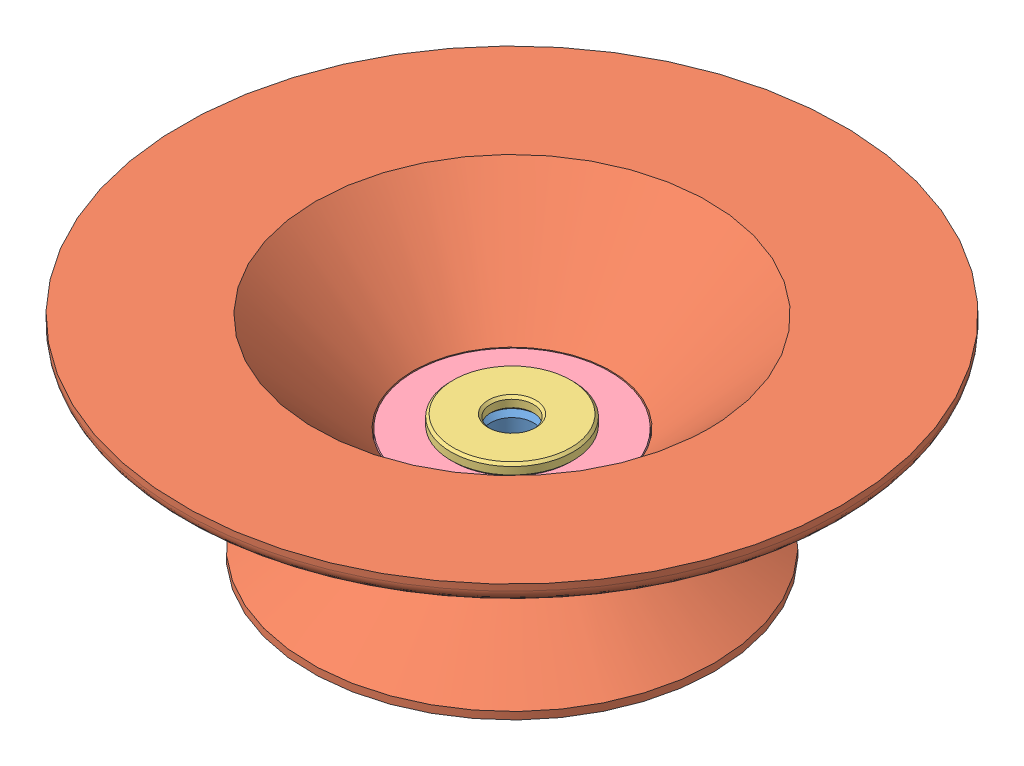
SolidWorks assembly Assem1, configuration Default. Lengths in mm.
Overall size (53.93 18.5 53.93).
4 component instances, 4 part files, 6 mates.
Components (placement in the parent):
- standoff-1: standoff [Default] at origin size (12 10.5 12)
- outer guide-1: outer guide [Default] at (0 8 0) x (1 0 0) z (0 -1 0) size (53.93 53.93 17.5)
- washer-1: washer [Default] at (0 11.5 0) x (1 0 0) z (0 -1 0) size (10 10 1)
- bearing-1: bearing [Default] at (0 10.5 0) x (0 -1 0) z (0 0 1) size (5 16 16)
Mates (geometry in assembly coordinates):
- Concentric1: concentric aligned: circle of standoff-1; cylinder of outer guide-1 through (0 -154.7216 0) axis (0 -1 0) radius 7.5
- Concentric2: concentric anti-aligned: cylinder of standoff-1 through (0 -1052.6268 0) axis (0 -1 0) radius 3.9; cylinder of washer-1 through (0 10.5 0) axis (0 1 0) radius 5
- Coincident1: coincident anti-aligned: plane of standoff-1 through (1.75 10.5 0) normal (0 1 0); plane of washer-1 through (0 10.5 0) normal (0 -1 0)
- Concentric3: concentric anti-aligned: cylinder of standoff-1 through (0 -1052.6268 0) axis (0 -1 0) radius 3.9; cylinder of bearing-1 through (0 198.6922 0) axis (0 1 0) radius 4
- Coincident2: coincident anti-aligned: plane of standoff-1 through (3.9 5.5 0) normal (0 1 0); plane of bearing-1 through (8 5.5 0) normal (0 -1 0)
- Coincident3: coincident aligned: circle of outer guide-1; plane of bearing-1 through (8 5.5 0) normal (0 -1 0)
